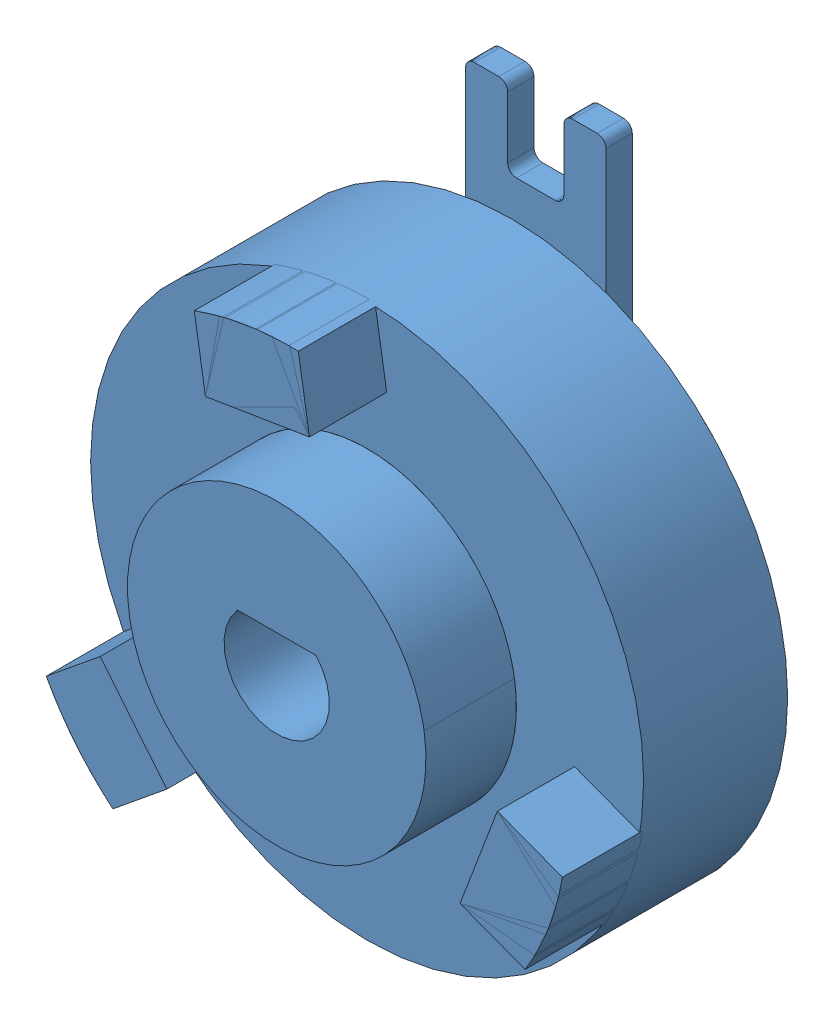
SolidWorks assembly hand_model, configuration Default. Lengths in mm.
Overall size (31.5 31.5 0).
2 component instances, 2 part files, 0 mates.
Components (placement in the parent):
- MIC3.5T-25-1: MIC3.5T-25 [Default] at (15.1943 25.018 25.3616) size (34.49 38.19 17.95) (hidden)
- Part5^hand_model-1: Part5^hand_model [Default] at origin size (31.5 31.5 0) (virtual)
